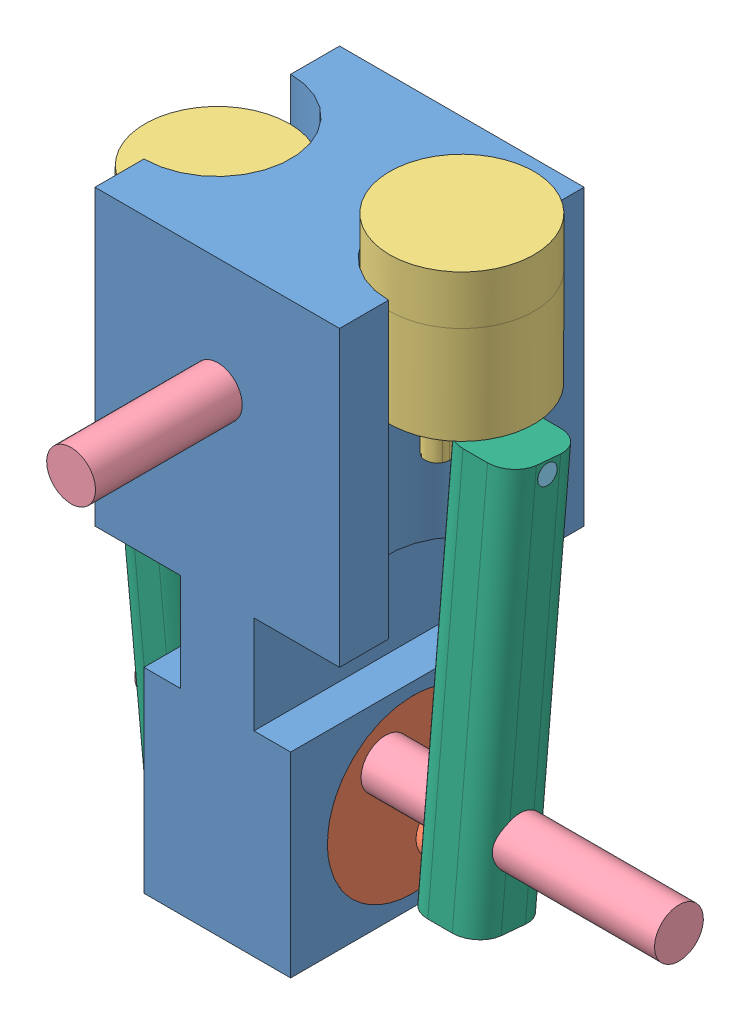
SolidWorks assembly piston, configuration Default. Lengths in mm.
Overall size (298.96 335.86 203.2).
12 component instances, 6 part files, 22 mates.
Components (placement in the parent):
- Part1-1: Part1 [Default] at origin size (127 304.8 127)
- Part2-1: Part2 [Default] at (101.6 -101.6 -63.5) x (0 0.826997 0.562206) z (0 -0.562206 0.826997) size (88.9 76.2 88.9)
- Part3-4: Part3 [Default] at (127 147.1071 -63.5) x (-1 0 0) z (0 0 1) size (74.93 101.6 74.93)
- Part3-6: Part3 [Default] at (0 105.0957 -63.5) x (1 0 0) z (0 0 -1) size (74.93 101.6 74.93)
- bigsil-1: bigsil [Default] at (139.7 -80.5943 -49.22) x (0 -0.124471 -0.992223) z (0 -0.992223 0.124471) size (25.4 114.3 25.4)
- bigsil-2: bigsil [Default] at (25.4 -80.5943 -49.22) x (0 0.99999 0.00454) z (0 0.00454 -0.99999) size (25.4 114.3 25.4)
- bigsil-3: bigsil [Default] at (-44.4417 -122.6057 -77.78) x (0 0.694614 0.719383) z (0 0.719383 -0.694614) size (25.4 114.3 25.4)
- smallsil-1: smallsil [Default] at (5.844 35.2457 -63.5) x (0 0.410437 -0.911889) z (0 0.911889 0.410437) size (10.16 50.8 10.16)
- smallsil-2: smallsil [Default] at (120.6417 77.2571 -63.5) x (0 -1 0) z (0 0 1) size (10.16 50.8 10.16)
- Part4-9: Part4 [Default] at (152.3917 83.5813 -64.0721) x (0 -0.090097 -0.995933) z (-1 0 0) size (38.1 203.2 38.1)
- Part4-10: Part4 [Default] at (-25.3917 41.5698 -62.9279) x (0 0.090097 -0.995933) z (-1 0 0) size (38.1 203.2 38.1)
- bigsil-4: bigsil [Default] at (63.785 92.6827 -38.1) x (0.999973 -0.007299 0) z (-0.007299 -0.999973 0) size (25.4 114.3 25.4)
Mates (geometry in assembly coordinates):
- Concentric1: concentric: cylinder of Part1-1 through (249.428 -101.6 -63.5) axis (-1 0 0) radius 44.45; cylinder of Part2-1 through (25.4 -101.6 -63.5) axis (1 0 0) radius 44.45
- Coincident1: coincident: plane of Part1-1 through (101.6 -50.8 13.716) normal (1 0 0); plane of Part2-1 through (101.6 -101.6 -63.5) normal (1 0 0)
- Concentric8: concentric: cylinder of Part1-1 through (127 152.4 -63.5) axis (0 -1 0) radius 38.1; cylinder of Part3-4 through (127 70.9071 -63.5) axis (0 1 0) radius 37.4396
- Concentric10: concentric: cylinder of Part1-1 through (0 0 -63.5) axis (0 1 0) radius 38.1; cylinder of Part3-6 through (0 28.8957 -63.5) axis (0 1 0) radius 37.4396
- Concentric11: concentric: cylinder of Part2-1 through (25.4 -80.5943 -49.22) axis (1 0 0) radius 12.7; cylinder of bigsil-1 through (254 -80.5943 -49.22) axis (-1 0 0) radius 12.7
- Coincident3: coincident: plane of bigsil-1 through (139.7 -80.5943 -49.22) normal (-1 0 0); plane of bigsil-2 through (139.7 -80.5943 -49.22) normal (1 0 0)
- Concentric16: concentric: cylinder of Part2-1 through (25.4 -122.6057 -77.78) axis (1 0 0) radius 12.7; cylinder of bigsil-3 through (69.8583 -122.6057 -77.78) axis (-1 0 0) radius 12.7
- Concentric20: concentric: cylinder of Part3-4 through (50.8 77.2571 -63.5) axis (1 0 0) radius 5.08; cylinder of smallsil-2 through (171.4417 77.2571 -63.5) axis (-1 0 0) radius 5.08
- Concentric24: concentric: cylinder of Part2-1 through (25.4 -80.5943 -49.22) axis (1 0 0) radius 12.7; cylinder of bigsil-2 through (139.7 -80.5943 -49.22) axis (-1 0 0) radius 12.7
- Concentric25: concentric: cylinder of bigsil-1 through (254 -80.5943 -49.22) axis (-1 0 0) radius 12.7; cylinder of bigsil-2 through (139.7 -80.5943 -49.22) axis (-1 0 0) radius 12.7
- Concentric27: concentric: cylinder of bigsil-2 through (139.7 -80.5943 -49.22) axis (-1 0 0) radius 12.7; cylinder of Part4-9 through (76.1917 -80.5943 -49.22) axis (1 0 0) radius 12.7
- Coincident5: coincident: plane of Part3-4 through (133.3417 96.3071 -50.7818) normal (1 0 0); plane of Part4-9 through (133.3417 -118.2202 -39.4402) normal (-1 0 0)
- Concentric28: concentric: cylinder of smallsil-2 through (171.4417 77.2571 -63.5) axis (-1 0 0) radius 5.08; cylinder of Part4-9 through (76.1917 77.2571 -63.5) axis (1 0 0) radius 5.08
- Coincident6: coincident: plane of Part2-1 through (25.4 -101.6 -63.5) normal (-1 0 0); plane of bigsil-2 through (25.4 -80.5943 -49.22) normal (-1 0 0)
- Concentric29: concentric: cylinder of Part3-6 through (76.2 35.2457 -63.5) axis (-1 0 0) radius 5.08; cylinder of smallsil-1 through (-44.956 35.2457 -63.5) axis (1 0 0) radius 5.08
- Concentric30: concentric: cylinder of bigsil-3 through (69.8583 -122.6057 -77.78) axis (-1 0 0) radius 12.7; cylinder of Part4-10 through (-101.5917 -122.6057 -77.78) axis (1 0 0) radius 12.7
- Coincident7: coincident: plane of Part3-6 through (-6.3417 54.2957 -76.2182) normal (-1 0 0); plane of Part4-10 through (-6.3417 -161.3759 -74.9115) normal (1 0 0)
- Concentric31: concentric: cylinder of smallsil-1 through (-44.956 35.2457 -63.5) axis (1 0 0) radius 5.08; cylinder of Part4-10 through (-101.5917 35.2457 -63.5) axis (1 0 0) radius 5.08
- Coincident8: coincident: plane of bigsil-3 through (-44.4417 -122.6057 -77.78) normal (-1 0 0); circle of Part4-10
- Coincident9: coincident: plane of smallsil-2 through (171.4417 77.2571 -63.5) normal (1 0 0); plane of Part4-9 through (171.4417 -118.2202 -39.4402) normal (1 0 0)
- Concentric32: concentric: cylinder of Part1-1 through (63.785 92.6827 -61.214) axis (0 0 1) radius 12.7; cylinder of bigsil-4 through (63.785 92.6827 76.2) axis (0 0 -1) radius 12.7
- Distance1: distance = 76.2 mm: plane of bigsil-4 through (63.785 92.6827 76.2) normal (0 0 1); plane of Part1-1 through (0 152.4 0) normal (0 0 1)
